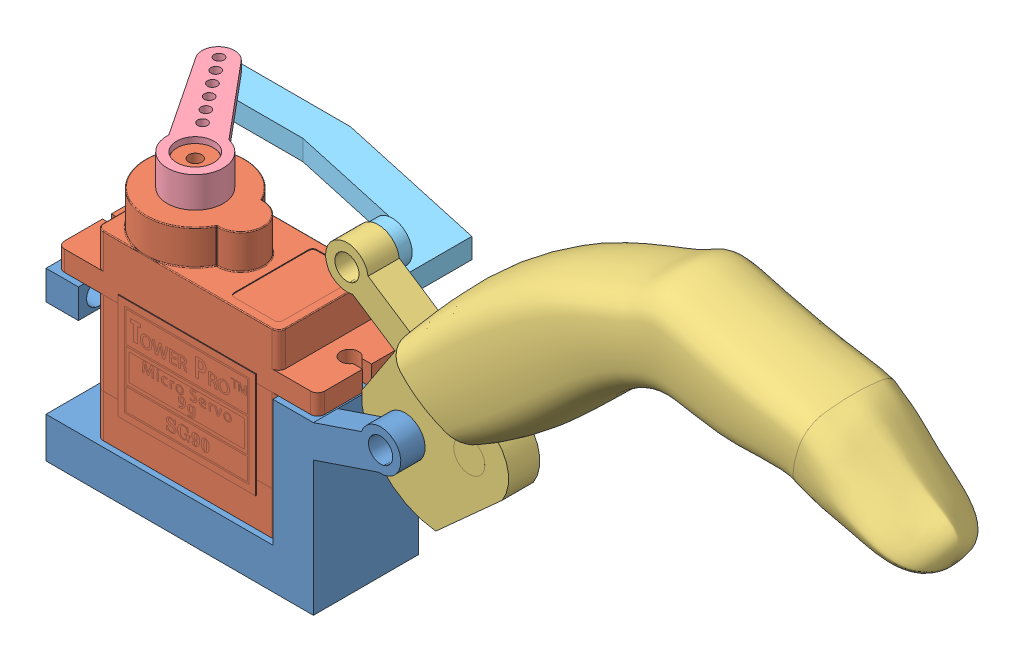
SolidWorks assembly Assemsbo3, configuration Default. Lengths in mm.
Overall size (109.85 85.01 22.87).
5 component instances, 5 part files, 12 mates.
Components (placement in the parent):
- support servo-1: support servo [Default] at (18.4779 5.908 35.2176) size (43.79 24.31 13)
- SG90 - Micro Servo 9g - Tower Pro.1-1: SG90 - Micro Servo 9g - Tower Pro.1 [Peça] at (18.7479 21.358 41.4176) size (32.1 29.95 12.4)
- sboo3-1: sboo3 [Predeterminado] at (43.2089 33.1961 43.1409) x (-0.835173 0.549987 0) z (-0.549987 -0.835173 0) size (61.55 12.45 61.26)
- SG90 - Micro Servo 9g - Tower Pro.2-1: SG90 - Micro Servo 9g - Tower Pro.2 [Peça] at (13.5979 41.358 41.4176) x (0.598334 0 0.801247) z (-0.801247 0 0.598334) size (19.5 3.8 6.9)
- sbo3servo-1: sbo3servo [Default] at (42.0109 39.958 31.9287) x (-1 0 0) z (0 -1 0) size (35.61 13.73 7.04)
Mates (geometry in assembly coordinates):
- Concentric4: concentric aligned: circle of support servo-1; cylinder of sboo3-1 through (43.2702 27.7158 45.0676) axis (0 0 -1) radius 1.5
- Coincident4: coincident anti-aligned: plane of support servo-1 through (18.4779 5.908 41.2176) normal (0 0 1); plane of sboo3-1 through (49.2967 36.2494 41.2176) normal (0 0 -1)
- Concentric5: concentric anti-aligned: line of SG90 - Micro Servo 9g - Tower Pro.1-1; axis of SG90 - Micro Servo 9g - Tower Pro.2-1 through (13.5979 39.558 41.4176) axis (0 -1 0)
- Coincident5: coincident anti-aligned: plane of SG90 - Micro Servo 9g - Tower Pro.1-1 through (13.5979 37.558 41.4176) normal (0 1 0); plane of SG90 - Micro Servo 9g - Tower Pro.2-1 through (13.5979 37.558 41.4176) normal (0 -1 0)
- Concentric16: concentric aligned: cylinder of support servo-1 through (4.8479 21.508 41.4176) axis (0 1 0) radius 1.1; cylinder of SG90 - Micro Servo 9g - Tower Pro.1-1 through (4.8479 10.808 41.4176) axis (0 1 0) radius 1.1
- Coincident7: coincident anti-aligned: plane of support servo-1 through (34.9779 26.508 48.2176) normal (0 1 0); plane of SG90 - Micro Servo 9g - Tower Pro.1-1 through (3.5479 26.508 46.6676) normal (0 -1 0)
- Concentric9: concentric aligned: cylinder of SG90 - Micro Servo 9g - Tower Pro.2-1 through (4.952 41.358 29.8396) axis (0 1 0) radius 0.6; cylinder of sbo3servo-1 through (4.952 37.458 29.8396) axis (0 1 0) radius 1.1551
- Coincident8: coincident aligned: circle of SG90 - Micro Servo 9g - Tower Pro.2-1; plane of sbo3servo-1 through (4.952 39.958 29.8396) normal (0 1 0)
- Parallel2: parallel aligned: cylinder of support servo-1 through (32.6109 21.508 41.4176) axis (0 1 0) radius 1.2; cylinder of SG90 - Micro Servo 9g - Tower Pro.1-1 through (32.6479 10.808 41.4176) axis (0 1 0) radius 1.1
- Parallel3: parallel aligned: line of support servo-1 through (34.9779 26.508 35.2176) axis (-1 0 0); line of SG90 - Micro Servo 9g - Tower Pro.1-1 through (33.9479 26.508 35.3176) axis (-1 0 0)
- Parallel4: parallel anti-aligned: cylinder of sboo3-1 through (35.9648 42.0354 45.0676) axis (0 0 -1) radius 1.5; cylinder of sbo3servo-1 through (35.9648 42.0354 39.4853) axis (0 0 1) radius 1.3
- Concentric22: concentric anti-aligned: cylinder of sboo3-1 through (35.9648 42.0354 45.0676) axis (0 0 -1) radius 1.5; cylinder of sbo3servo-1 through (35.9648 42.0354 39.4853) axis (0 0 1) radius 1.3
